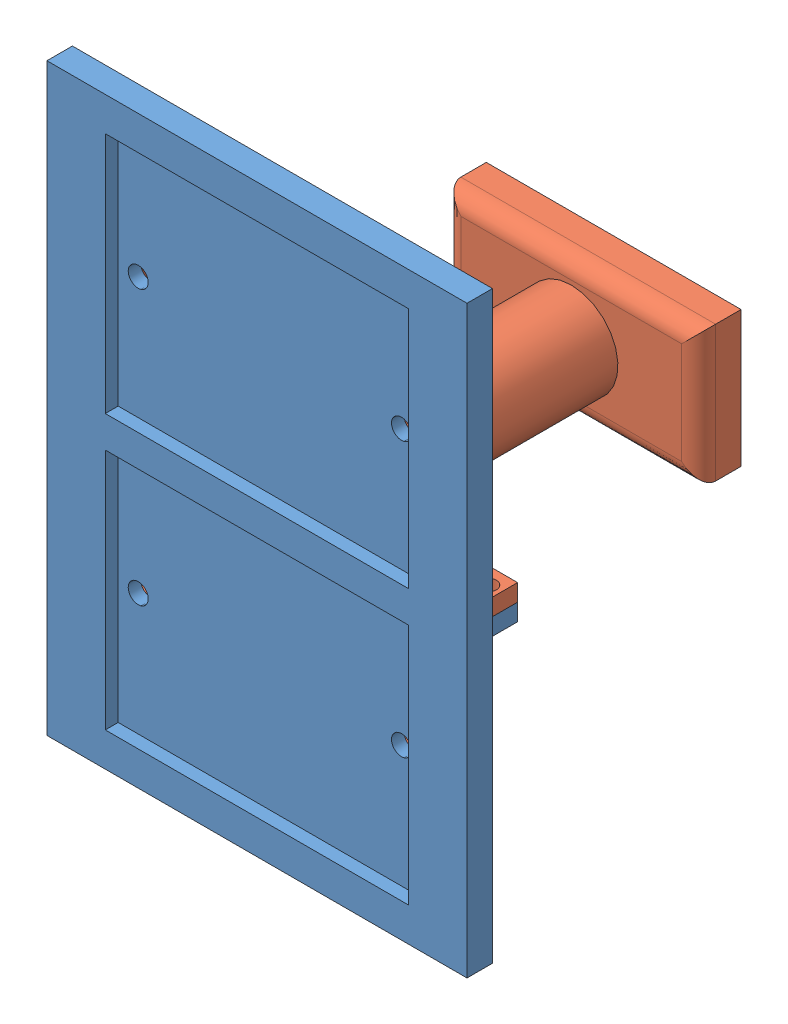
SolidWorks assembly Solar Panel Assembly, configuration Default. Lengths in mm.
Overall size (62.81 87.38 53.34).
2 component instances, 2 part files, 3 mates.
Components (placement in the parent):
- Front View Sketch-1: Front View Sketch [Default] at origin size (62.81 87.38 8.89)
- SolarPanel Wire Enlcosure-1: SolarPanel Wire Enlcosure [Default] at (0 -0.127 -3.81) x (-1 0 0) z (0 -1 0) size (60.17 49.53 51.49)
Mates (geometry in assembly coordinates):
- Concentric1: concentric anti-aligned: circle of Front View Sketch-1; circle of SolarPanel Wire Enlcosure-1
- Coincident2: coincident anti-aligned: plane of Front View Sketch-1 through (30.0854 -0.127 -8.89) normal (0 1 0); plane of SolarPanel Wire Enlcosure-1 through (0 -0.127 -8.89) normal (0 -1 0)
- Coincident3: coincident anti-aligned: plane of Front View Sketch-1 through (0 0 -3.81) normal (0 0 -1); plane of SolarPanel Wire Enlcosure-1 through (0 -0.127 -3.81) normal (0 0 1)
